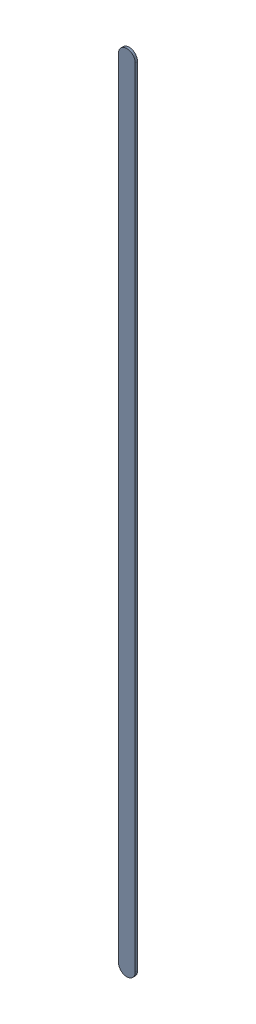
SolidWorks assembly Track (11.2mm,38mm)(11.2mm,49.951mm) on Top Layer, configuration Predeterminado. Lengths in mm.
Overall size (0.25 12.21 0.04).
2 component instances, 1 part files, 0 mates.
Components (placement in the parent):
- Track (11.2mm,38mm)(11.2mm,49.951mm) on Top Layer-1-1: Track (11.2mm,38mm)(11.2mm,49.951mm) on Top Layer-1 [Predeterminado] at (-68.317 -44.187 -0.0457) size (0.25 12.21 0.04)
  - Track (11.2mm,38mm)(11.2mm,49.951mm) on Top Layer-Part-1-1: Track (11.2mm,38mm)(11.2mm,49.951mm) on Top Layer-Part-1 [Predeterminado] at origin size (0.25 12.21 0.04)
